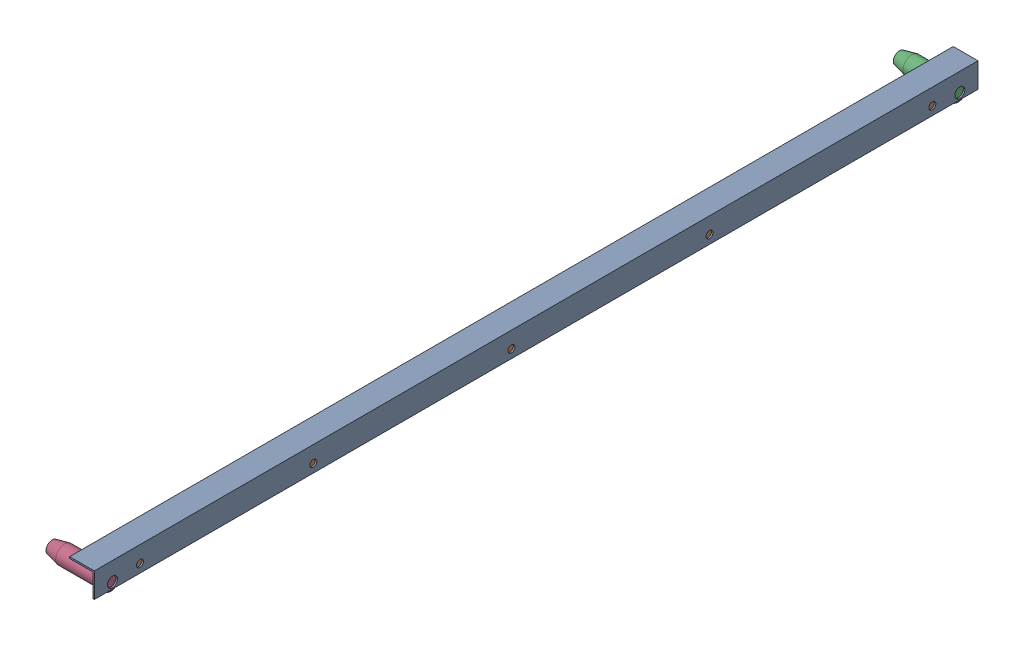
SolidWorks assembly FE-00007_, configuration Default. Lengths in mm.
Overall size (123.82 61.64 1812.92).
4 component instances, 3 part files, 0 mates.
Components (placement in the parent):
- FE-00007-01_-1: FE-00007-01_ [Default] at origin size (50.8 50.8 1812.92)
- FE-00007-02_-1: FE-00007-02_ [Default] at (20.0374 6.7331 75.4062) size (38.1 38.1 1662.11)
- FE-00007-03_-1: FE-00007-03_ [Default] at (-5.7674 6.8088 34.268) x (1 0 0) z (0 -0.935095 0.354397) size (120.65 36.51 36.51)
- FE-00007-03_-2: FE-00007-03_ [Default] at (-5.7674 4.7111 1775.6188) size (120.65 36.51 36.51)
